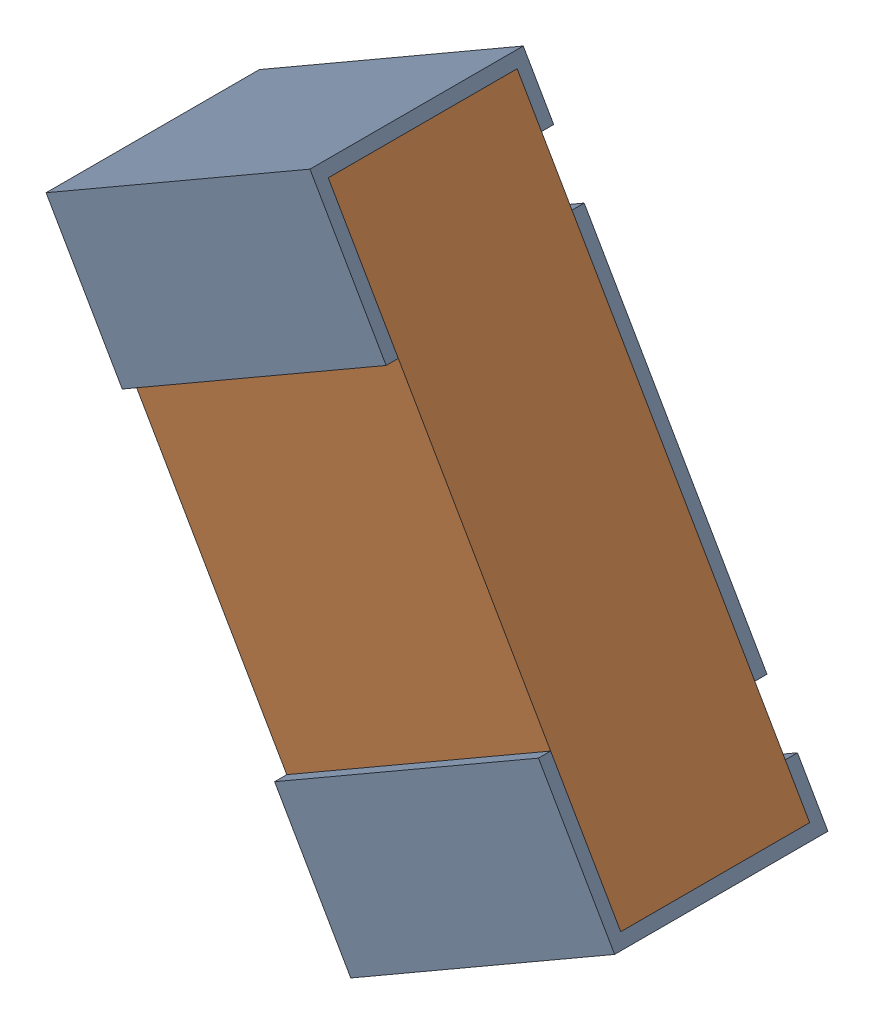
SolidWorks assembly R19, configuration Default. Lengths in mm.
Overall size (0.93 1.12 0.35).
3 component instances, 2 part files, 0 mates.
Components (placement in the parent):
- R19-subassembly-1-1: R19-subassembly-1 [Default] at (3.821 3.8771 -1.6307) x (0.5 -0.866025 0) z (0.866025 0.5 0) size (1 0.35 0.5)
  - 0402 resistor-1: 0402 resistor [Default] at origin size (1 0.35 0.5)
  - 0402 resistor-1-1: 0402 resistor-1 [Default] at origin size (0.96 0.31 0.5)
